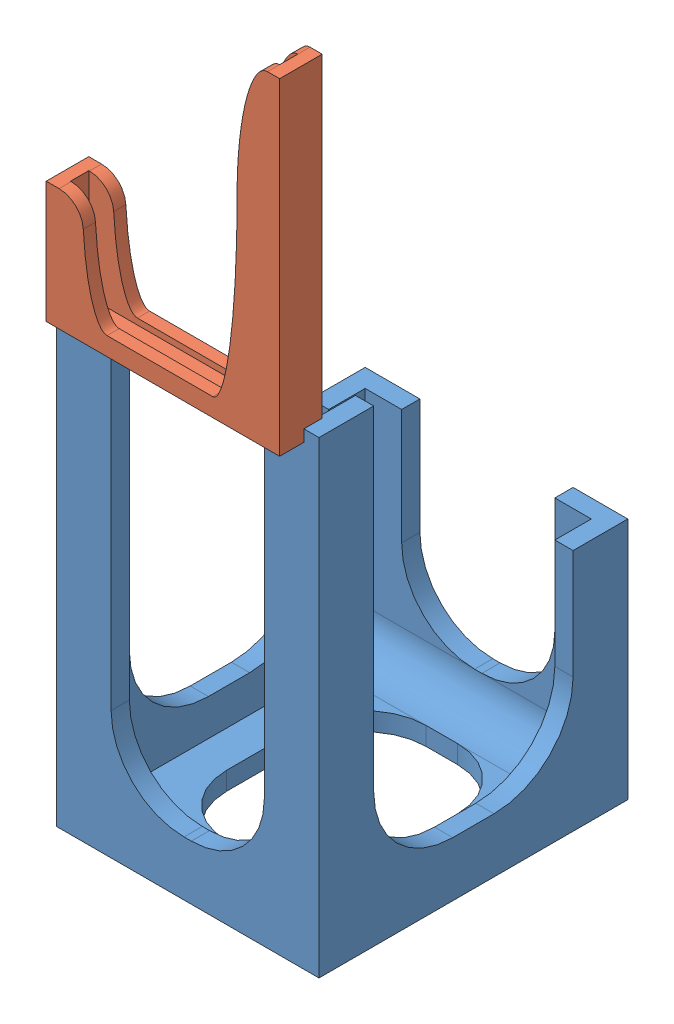
SolidWorks assembly Assem1, configuration Default. Lengths in mm.
Overall size (21.6 64.54 27.5).
2 component instances, 2 part files, 1 mates.
Components (placement in the parent):
- Motor+Kort-1: Motor+Kort [Default] at origin size (21.6 38.5 25.4)
- kretskorthållare-1: kretskorthållare [Default] at (-93.0247 6.3203 47.4802) x (0 -1 0) z (1 0 0) size (27 3.71 19.2)
Mates (geometry in assembly coordinates):
- Coincident2: coincident anti-aligned: plane of Motor+Kort-1 through (0 38.5 0) normal (0 1 0); line of Motor+Kort-1 through (-76.5701 38.5 40.9845) axis (0 0 1)
